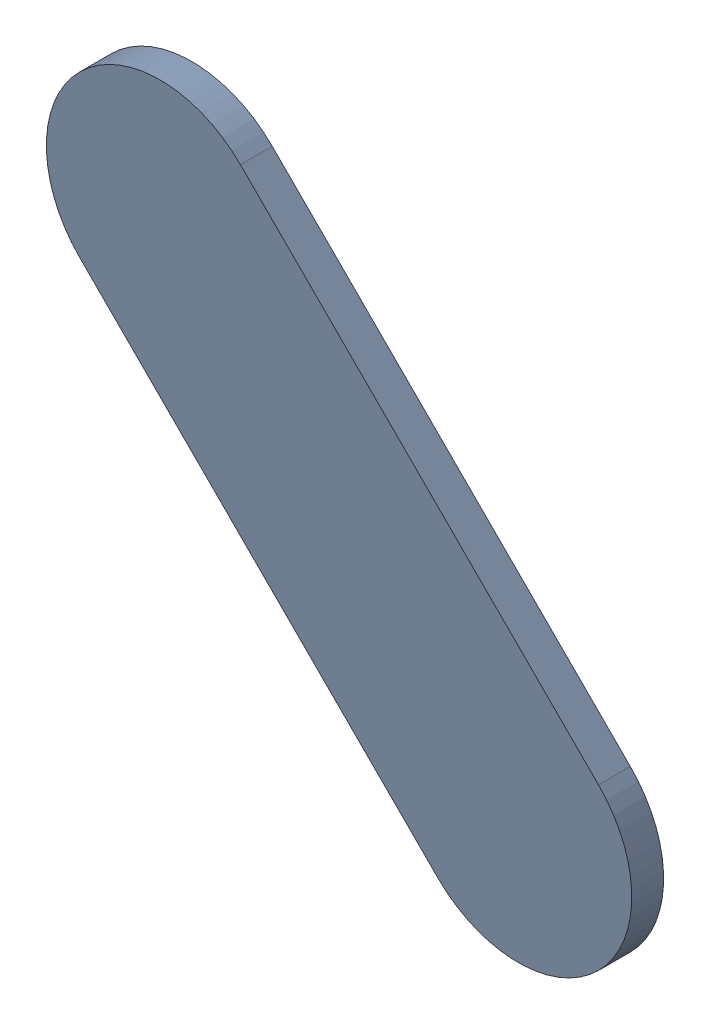
SolidWorks assembly Track (25.1mm,47.6mm)(25.5mm,47.2mm) on Bottom Layer, configuration Predeterminado. Lengths in mm.
Overall size (0.65 0.65 0.04).
2 component instances, 1 part files, 0 mates.
Components (placement in the parent):
- Track (25.1mm,47.6mm)(25.5mm,47.2mm) on Bottom Layer-1-1: Track (25.1mm,47.6mm)(25.5mm,47.2mm) on Bottom Layer-1 [Predeterminado] at (-68.317 -44.187 -0.4013) size (0.65 0.65 0.04)
  - Track (25.1mm,47.6mm)(25.5mm,47.2mm) on Bottom Layer-Part-1-1: Track (25.1mm,47.6mm)(25.5mm,47.2mm) on Bottom Layer-Part-1 [Predeterminado] at origin size (0.65 0.65 0.04)
